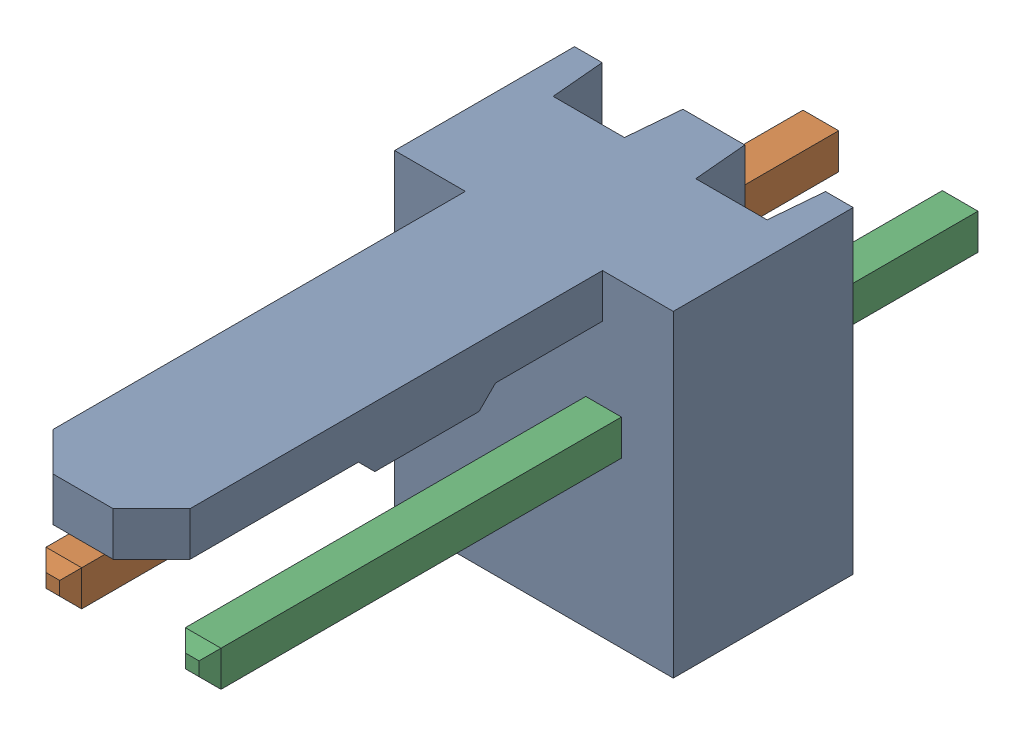
SolidWorks assembly Molex PCB 2 pin v2_1, configuration Predeterminado. Lengths in mm.
Overall size (5.08 5.79 14.92).
3 component instances, 2 part files, 0 mates.
Components (placement in the parent):
- BASE9710016_1-1: BASE9710016_1 [Predeterminado] at (2.54 2.895 -8.22) size (5.08 5.79 11.5)
- PINO9710016_1-1: PINO9710016_1 [Predeterminado] at (1.27 3.325 -0.72) size (0.65 0.65 14.2)
- PINO9710016_1-2: PINO9710016_1 [Predeterminado] at (3.81 3.325 -0.72) size (0.65 0.65 14.2)
